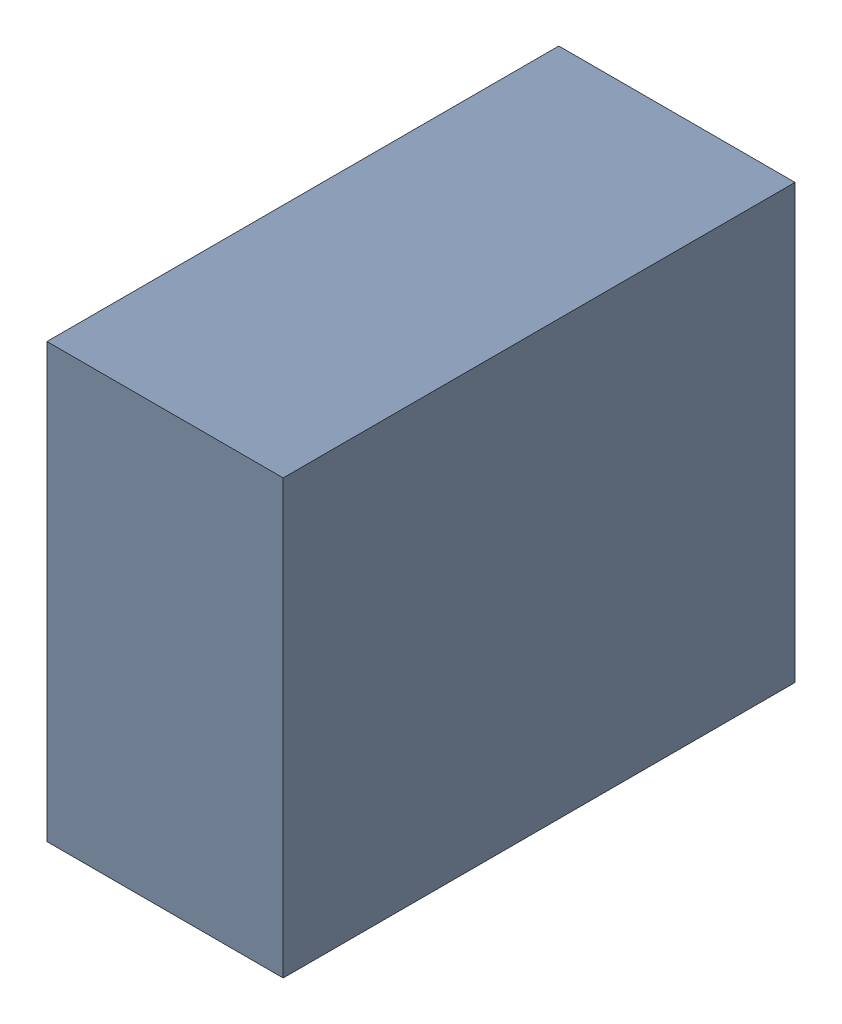
SolidWorks assembly C22_TDA4, configuration Standard. Lengths in mm.
Overall size (0.6 1.1 1.3).
2 component instances, 1 part files, 0 mates.
Components (placement in the parent):
- 885542376-1: 885542376 [Standard] at (4.78 -53.49 0) size (0.6 1.1 1.3)
  - Extruded_25-1: Extruded_25 [Standard] at origin size (0.6 1.1 1.3)
